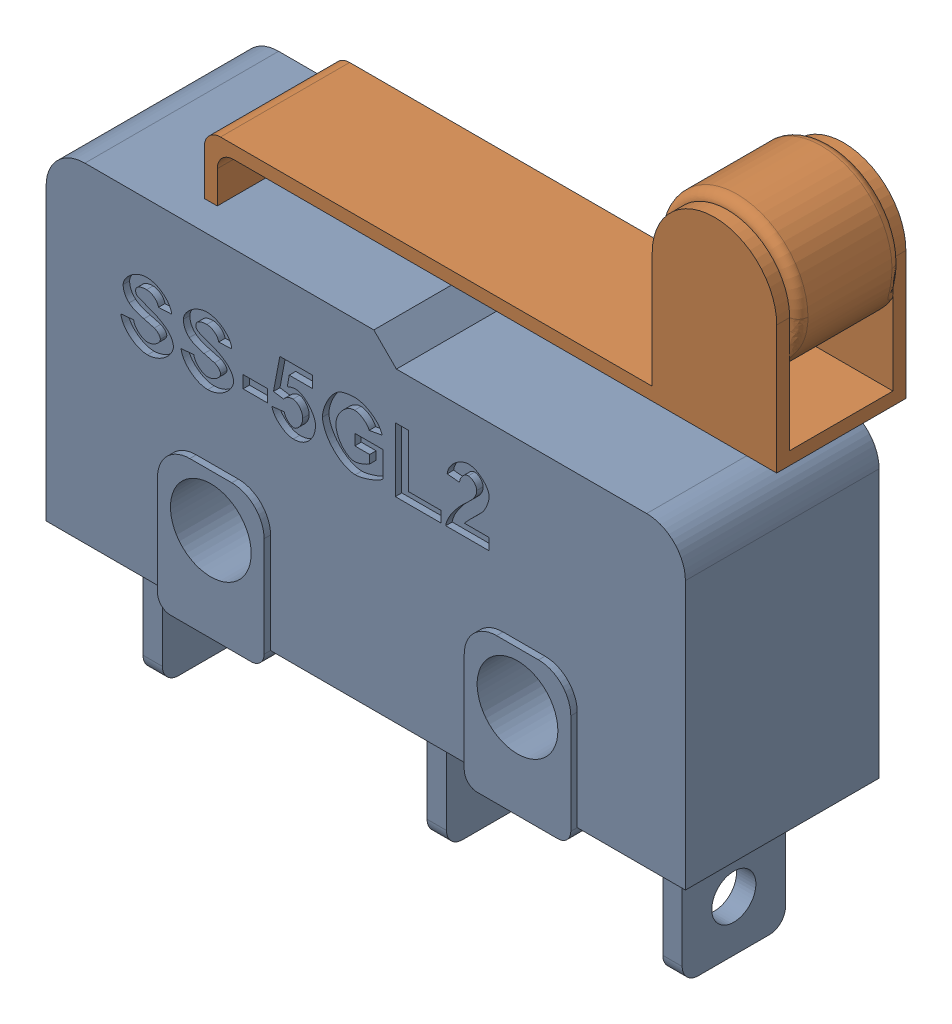
SolidWorks assembly MICROSWITCH_rolller_type, configuration MICROSWITCH_rolller_type. Lengths in mm.
Overall size (22 21.87 6.4).
2 component instances, 2 part files, 0 mates.
Components (placement in the parent):
- Mikrokapcsol_X_F3_test-1: Mikrokapcsol_X_F3_test [Mikrokapcsol_X_F3_test] at origin size (19.8 14.2 6.4)
- mikrokapcsol_X_F3_lemez-1: mikrokapcsol_X_F3_lemez [mikrokapcsol_X_F3_lemez] at (24.9751 11.8957 1.3) size (18 7.67 4)
